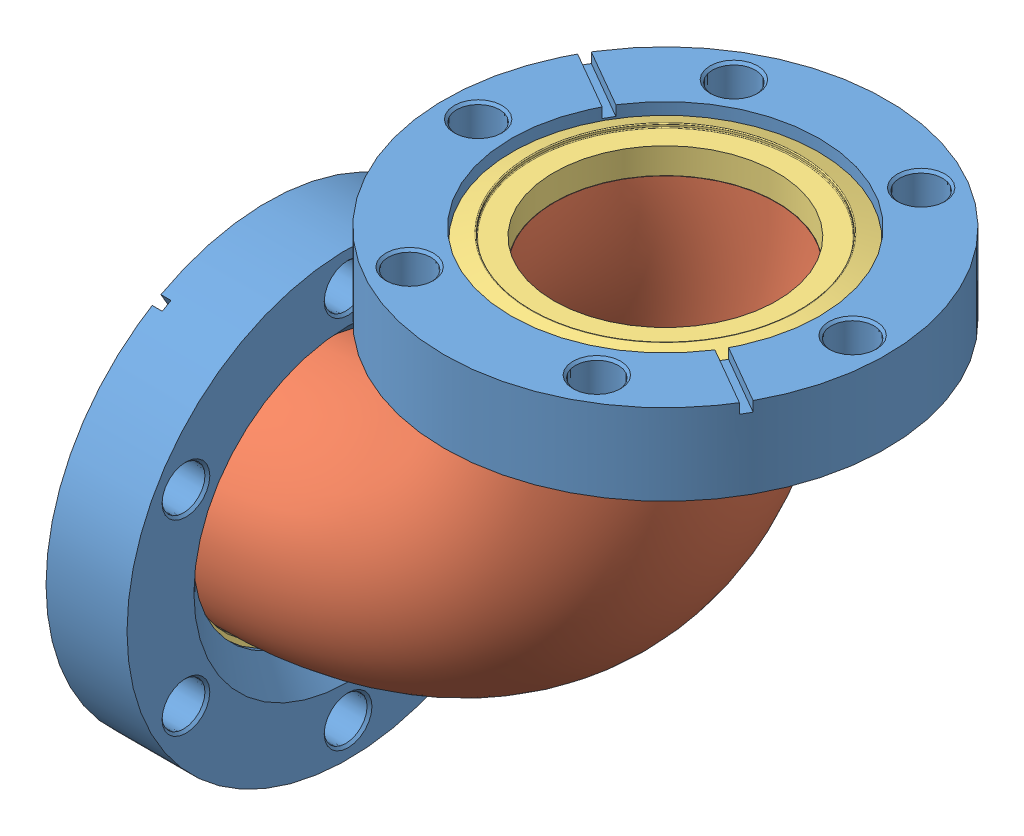
SolidWorks assembly 403002, configuration Default. Lengths in mm.
Overall size (97.13 97.13 69.34).
5 component instances, 3 part files, 10 mates.
Components (placement in the parent):
- 915002-1: 915002 [Default] at (6.2794 31.6121 63.3277) size (12.7 69.34 69.34)
- 403502-1: 403502 [Default] at (11.588 31.6121 63.3277) x (0 1 0) z (-1 0 0) size (76.2 38.1 76.2)
- 910014-1: 910014 [Default] at (6.9398 31.6121 63.3277) x (1 0 0) z (0 -0.036229 0.999344) size (6.91 48.06 48.06)
- 910014-2: 910014 [Default] at (68.738 93.4103 63.3277) x (0 -1 0) z (0 0 1) size (6.91 48.06 48.06)
- 915002-2: 915002 [Default] at (68.738 94.0707 63.3277) x (0 -1 0) z (0 0 1) size (12.7 69.34 69.34)
Mates (geometry in assembly coordinates):
- Concentric1: concentric aligned: cylinder of 915002-1 through (6.2794 31.6121 63.3277) axis (-1 0 0) radius 34.671; cylinder of 910014-1 through (6.9398 31.6121 63.3277) axis (-1 0 0) radius 24.0284
- Coincident1: coincident anti-aligned: plane of 915002-1 through (13.8994 51.4241 63.3277) normal (-1 0 0); plane of 910014-1 through (13.8994 55.6247 64.1982) normal (1 0 0)
- Concentric2: concentric aligned: circle of 403502-1; circle of 910014-1
- Coincident2: coincident anti-aligned: plane of 403502-1 through (11.588 31.6121 63.3277) normal (-1 0 0); plane of 910014-1 through (11.588 50.7765 64.0224) normal (1 0 0)
- Parallel2: parallel anti-aligned: plane of 403502-1 through (11.588 31.6121 63.3277) normal (0 0 -1)
- Concentric3: concentric aligned: cylinder of 910014-2 through (68.738 93.4103 63.3277) axis (0 1 0) radius 24.0284; cylinder of 915002-2 through (68.738 94.0707 63.3277) axis (0 1 0) radius 34.671
- Coincident5: coincident anti-aligned: plane of 910014-2 through (92.7664 86.4507 63.3277) normal (0 -1 0); plane of 915002-2 through (88.5349 86.4507 64.1005) normal (0 1 0)
- Concentric4: concentric anti-aligned: circle of 403502-1; cylinder of 910014-2 through (68.738 93.4103 63.3277) axis (0 1 0) radius 17.4625
- Coincident6: coincident anti-aligned: plane of 403502-1 through (68.738 88.7621 63.3277) normal (0 1 0); plane of 910014-2 through (87.915 88.7621 63.3277) normal (0 -1 0)
- Parallel3: parallel aligned: plane of 915002-2 through (68.738 94.0707 63.3277) normal (0 0 1)
